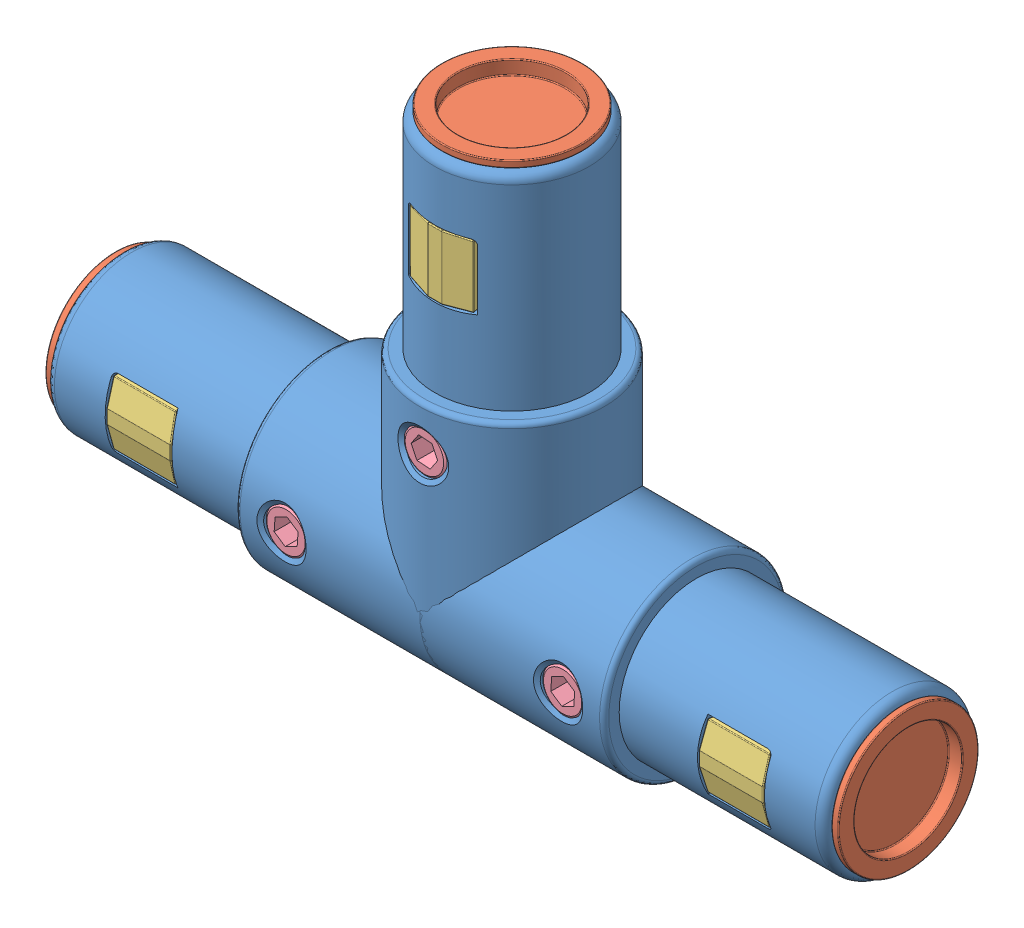
SolidWorks assembly Сборка1, configuration 00. Lengths in mm.
Overall size (172 106 40).
14 component instances, 4 part files, 0 mates.
Components (placement in the parent):
- SNSK.17.00.48. T-коннектор.V48-1: SNSK.17.00.48. T-коннектор.V48 [По умолчанию] at (-12.3382 -26.5465 -114.5) size (172 106 40)
  - SNSK.17.00.02. Коннетор.V48-1: SNSK.17.00.02. Коннетор.V48 [Условная резьба] at (11.9292 -3.6926 114.4998) x (0 0 -1) z (0 1 0) size (40 169 104.5)
  - SNSK.17.00.00. Заклушка для коннекторов лестничные системыV47-1: SNSK.17.00.00. Заклушка для коннекторов лестничные системыV47 [По умолчанию] at (-74.0708 -3.6926 114.4998) x (0 0 -1) z (0 -1 0) size (30.4 10 30.4)
  - SNSK.17.00.01.Фиксатор.V48-1: SNSK.17.00.01.Фиксатор.V48 [По умолчанию] at (-85.6188 -10.5926 119.8498) x (0 1 0) z (1 0 0) size (14.2 11.41 13.94)
  - socket set screw cone point_din-8: socket set screw cone point_din [DIN 914 - M10 x 12-N] at (-18.0708 -3.6926 133.4998) x (0 0 -1) z (0.067862 0.997695 0) size (12 10 10)
  - SNSK.17.00.00. Заклушка для коннекторов лестничные системыV47-10: SNSK.17.00.00. Заклушка для коннекторов лестничные системыV47 [По умолчанию] at (11.9292 -3.6926 28.4998) x (1 0 0) z (0 -1 0) size (30.4 10 30.4) (suppressed, hidden)
  - socket set screw cone point_din-16: socket set screw cone point_din [DIN 914 - M10 x 12-N] at (-7.0708 -3.6926 84.4998) x (1 0 0) z (0 0.997695 0.067862) size (12 10 10) (suppressed, hidden)
  - SNSK.17.00.01.Фиксатор.V48-9: SNSK.17.00.01.Фиксатор.V48 [По умолчанию] at (6.5792 -10.5926 16.9518) x (0 1 0) z (0 0 1) size (14.2 11.41 13.94) (suppressed, hidden)
  - SNSK.17.00.01.Фиксатор.V48-10: SNSK.17.00.01.Фиксатор.V48 [По умолчанию] at (109.4773 3.2074 119.8498) x (0 -1 0) z (-1 0 0) size (14.2 11.41 13.94)
  - SNSK.17.00.01.Фиксатор.V48-11: SNSK.17.00.01.Фиксатор.V48 [По умолчанию] at (5.0292 93.8555 119.8498) x (1 0 0) z (0 -1 0) size (14.2 11.41 13.94)
  - SNSK.17.00.00. Заклушка для коннекторов лестничные системыV47-11: SNSK.17.00.00. Заклушка для коннекторов лестничные системыV47 [По умолчанию] at (97.9292 -3.6926 114.4998) x (0 0 -1) z (0 1 0) size (30.4 10 30.4)
  - SNSK.17.00.00. Заклушка для коннекторов лестничные системыV47-12: SNSK.17.00.00. Заклушка для коннекторов лестничные системыV47 [По умолчанию] at (11.9292 82.3074 114.4998) x (0 0 -1) z (-1 0 0) size (30.4 10 30.4)
  - socket set screw cone point_din-17: socket set screw cone point_din [DIN 914 - M10 x 12-N] at (41.9292 -3.6926 133.4998) x (0 0 -1) z (-0.067862 -0.997695 0) size (12 10 10)
  - socket set screw cone point_din-18: socket set screw cone point_din [DIN 914 - M10 x 12-N] at (11.9292 26.3074 133.4998) x (0 0 -1) z (0.997695 -0.067862 0) size (12 10 10)
